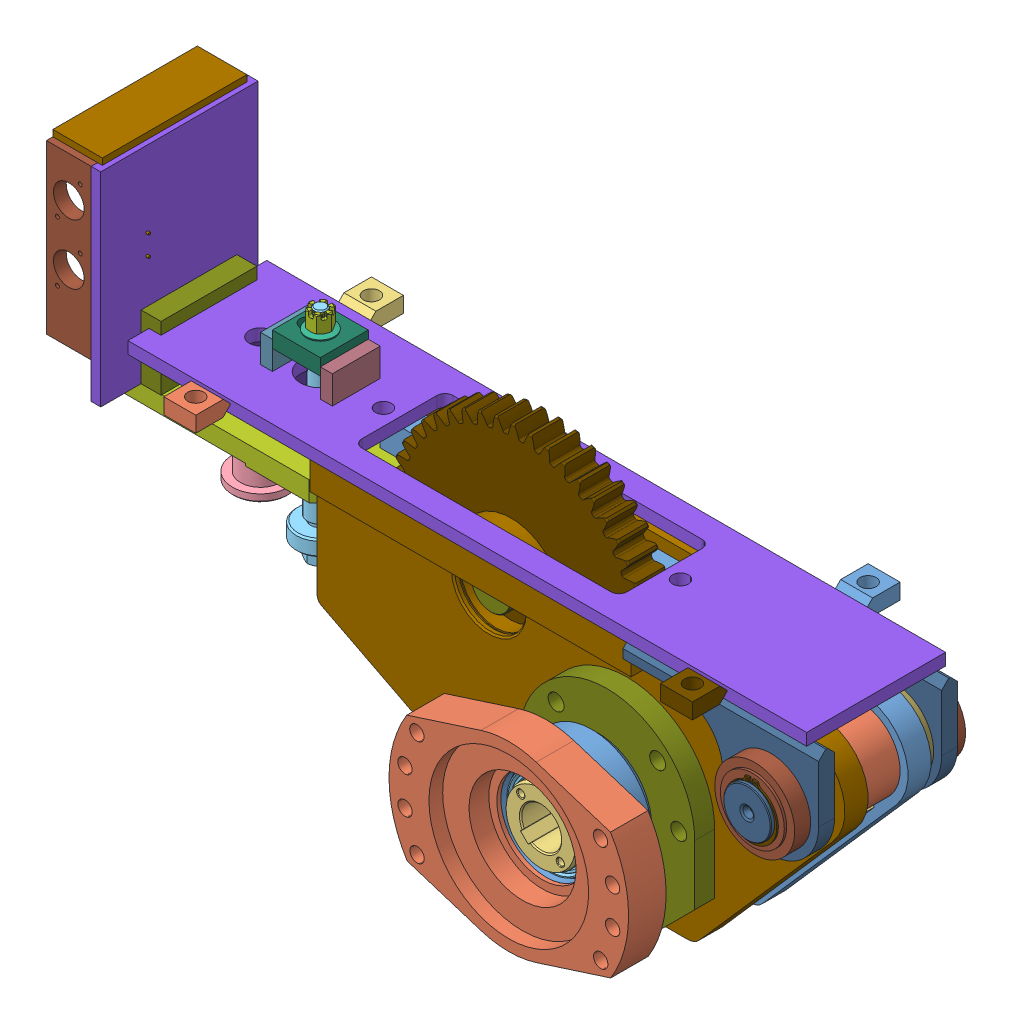
SolidWorks assembly g1_3_1_1, configuration 默认. Lengths in mm.
Overall size (943 530 331.8).
109 component instances, 72 part files, 43 mates.
Components (placement in the parent):
- g1_3_1_1_5_1-1: g1_3_1_1_5_1 [默认] at (308.7423 -95 30) x (-1 0 0) z (0 1 0) size (926 108 318.6)
  - g1_3_1_1_5-1_af1_1-1: g1_3_1_1_5-1_af1_1 [默认] at origin size (661 29 318.6)
  - g1_3_1_1_5-2_af0_1-1: g1_3_1_1_5-2_af0_1 [默认] at (-213.2 29 0) size (100 50 100)
  - g1_3_1_1_5-4_1-1: g1_3_1_1_5-4_1 [默认] at (-149.9151 54 -132.7301) x (0 1 0) z (-0.659692 0 0.751536) size (50 10 223)
  - g1_3_1_1_5-5_1-1: g1_3_1_1_5-5_1 [默认] at (20.5 54 -217) x (1 0 0) z (0 1 0) size (194 10 50)
  - g1_3_1_1_5-6_1-1: g1_3_1_1_5-6_1 [默认] at (248.4498 54 -161.5242) x (0 1 0) z (0.890083 0 0.455798) size (50 10 284)
  - g1_3_1_1_5-7_1-1: g1_3_1_1_5-7_1 [默认] at (377.8 54 -43.9) x (0 0 -1) z (0 1 0) size (87 10 50)
  - g1_3_1_1_5-9_af0_1-1: g1_3_1_1_5-9_af0_1 [默认] at (502.8 54 24.6) x (1 0 0) z (0 1 0) size (300 25 108)
  - g1_3_1_1_5-8_1-1: g1_3_1_1_5-8_1 [默认] at (437.8 54 49.6) x (1 0 0) z (0 1 0) size (60 50 60)
  - g1_3_1_1_5-1_af0_1-1: g1_3_1_1_5-1_af0_1 [默认] at (0 79 0) size (661 29 318.6)
- g1_3_1_1_4_1-1: g1_3_1_1_4_1 [默认] at (521.9423 -95 -33.3) x (1 0 0) z (0 -1 0) size (80 234 80)
  - g1_3_1_1_4-1_1-1: g1_3_1_1_4-1_1 [默认] at origin size (60 234 60.04)
  - g1_3_1_1_4-3_1-2: g1_3_1_1_4-3_1 [默认] at (0 224.3 0) size (80 3 80)
  - g1_3_1_1_4-2_1-1: g1_3_1_1_4-2_1 [默认] at (0 174.3 0) size (72 50 72)
  - g1_3_1_1_4-2_1-2: g1_3_1_1_4-2_1 [默认] at (0 9.7 0) size (72 50 72)
  - g1_3_1_1_4-2_1-3: g1_3_1_1_4-2_1 [默认] at (0 62.7 0) size (72 50 72)
  - g1_3_1_1_4-2_1-4: g1_3_1_1_4-2_1 [默认] at (0 121.3 0) size (72 50 72)
- g1_3_1_1_2_1-1: g1_3_1_1_2_1 [默认] at (308.7423 -195.4 0) x (0.999998 0.002137 0) z (0.002137 -0.999998 0) size (219.6 152 245)
  - g1_3_1_1_2-1_1-1: g1_3_1_1_2-1_1 [默认] at origin size (219.6 61 245)
  - g1_3_1_1_2-2_1-1: g1_3_1_1_2-2_1 [默认] at (0 152 0) x (-0.047609 0 0.998866) z (0 1 0) size (120.16 120.16 117)
  - g1_3_1_1_2-3_1-1: g1_3_1_1_2-3_1 [默认] at (-20.1525 129 20.1525) x (0 -1 0) z (0.707107 0 0.707107) size (28 11 14)
- g1_3_1_1_3_1-1: g1_3_1_1_3_1 [默认] at (135.9423 -78.4 83.75) x (0 0 -1) z (0 -1 0) size (103.5 321.87 322.01)
  - g1_3_1_1_3-1_1-1: g1_3_1_1_3-1_1 [默认] at origin size (103.5 52 52)
  - 16x10x45_gb1096_1-1: 16x10x45_gb1096_1 [默认] at (-0.5 0 25) x (1 0 0) z (0 0 -1) size (45 16 10)
  - _X2_60F08F6E_X0_g1_3_1_1_3-2_1-1: _X2_60F08F6E_X0_g1_3_1_1_3-2_1 [默认] at (25 0 0) x (0 0 1) z (1 0 0) size (322.01 321.87 50.08)
- g1_3_1_1_1_2-1: g1_3_1_1_1_2 [默认] at (308.7423 -195.4 123.8) x (0.999998 0.002137 0) z (0.002137 -0.999998 0) size (300 165.8 228)
  - g1_3_1_1_1_1_1-1: g1_3_1_1_1_1_1 [默认] at origin size (300 112 228)
    - g1_3_1_1_1_1-2_af0_1-1: g1_3_1_1_1_1-2_af0_1 [默认] at (0 50 0) size (150 65 150)
    - g1_3_1_1_1_1-3_af0_1-1: g1_3_1_1_1_1-3_af0_1 [默认] at (0 140 0) size (300 47 228)
  - g1_3_1_1_1-2_1-1: g1_3_1_1_1-2_1 [默认] at (0 122.2 0) x (0.707107 0 0.707107) z (0.707107 0 -0.707107) size (90 126 90)
  - g1_3_1_1_1-1_1-1: g1_3_1_1_1-1_1 [默认] at (0 77 0) x (0 1 0) z (0 0 1) size (20 110 110)
  - b90x110x12_gb9877_1_1-1: b90x110x12_gb9877_1_1 [默认] at (0 66.9 0) size (108.6 17.9 108.6)
    - b90x110x12_gb9877_1_rubber_1-1: b90x110x12_gb9877_1_rubber_1 [默认] at origin size (108.6 12 108.6)
    - b90x110x12_gb9877_1_frame_1-1: b90x110x12_gb9877_1_frame_1 [默认] at (0 -2.4 0) x (-1 0 0) z (0 0 1) size (107.2 9.5 107.2)
  - b90x110x12_gb9877_1_1-2: b90x110x12_gb9877_1_1 [默认] at (0 104.8 0) size (108.6 17.9 108.6)
    - b90x110x12_gb9877_1_rubber_1-1: b90x110x12_gb9877_1_rubber_1 [默认] at origin size (108.6 12 108.6)
    - b90x110x12_gb9877_1_frame_1-1: b90x110x12_gb9877_1_frame_1 [默认] at (0 -2.4 0) x (-1 0 0) z (0 0 1) size (107.2 9.5 107.2)
  - 80_gb894_1_1-1: 80_gb894_1_1 [默认] at (-2.4 11.1 -38.1746) x (1 0 0) z (0 -1 0) size (85.83 90.87 2.5)
- g1_3_1_1_6_1-1: g1_3_1_1_6_1 [默认] at (135.9423 0 84) x (-1 0 0) z (0 0 1) size (875 200 260)
  - g1_3_1_1_6-4_af0_1-1: g1_3_1_1_6-4_af0_1 [默认] at origin size (850 15 174)
  - g1_3_1_1_6-8_1-1: g1_3_1_1_6-8_1 [默认] at (0 40 57) x (1 0 0) z (0 -1 0) size (402 20 44.8)
  - g1_3_1_1_6-8_1-2: g1_3_1_1_6-8_1 [默认] at (0 40 -77) x (1 0 0) z (0 -1 0) size (402 20 44.8)
  - g1_3_1_1_6-1_1-1: g1_3_1_1_6-1_1 [默认] at (-386 95 -87) x (1 0 0) z (0 -1 0) size (245 20 140)
  - g1_3_1_1_6-1_1-2: g1_3_1_1_6-1_1 [默认] at (-386 95 67) x (1 0 0) z (0 -1 0) size (245 20 140)
  - g1_3_1_1_6-3_1-1: g1_3_1_1_6-3_1 [默认] at (-386 95 87) x (-1 0 0) z (0 1 0) size (100 20 100)
  - g1_3_1_1_6-3_1-2: g1_3_1_1_6-3_1 [默认] at (-386 95 -107) x (-1 0 0) z (0 1 0) size (100 20 100)
  - g1_3_1_1_6-2_1-1: g1_3_1_1_6-2_1 [默认] at (-386 95 57) x (-1 0 0) z (0 1 0) size (100 10 100)
  - g1_3_1_1_6-2_1-2: g1_3_1_1_6-2_1 [默认] at (-386 95 -57) x (1 0 0) z (0 1 0) size (100 10 100)
  - g1_3_1_1_6-9_1-1: g1_3_1_1_6-9_1 [默认] at (220 -17 0) x (0 1 0) z (0 0 -1) size (35 15 60)
  - g1_3_1_1_6-9_af0_1-1: g1_3_1_1_6-9_af0_1 [默认] at (310 -17 0) x (0 1 0) z (0 0 1) size (35 15 60)
  - g1_3_1_1_6-10_1-1: g1_3_1_1_6-10_1 [默认] at (265 -45 0) size (60 20 60)
  - g1_3_1_1_6-12_af0_1-1: g1_3_1_1_6-12_af0_1 [默认] at (434 25 0.5) x (0 0 1) z (0 -1 0) size (120 25 80)
  - g1_3_1_1_6-11_af0_1-1: g1_3_1_1_6-11_af0_1 [默认] at (357 15 0) size (94 40 60)
  - g1_3_1_1_6-5_af0_1-1: g1_3_1_1_6-5_af0_1 [默认] at (-311 -5 108.5) x (0 0 -1) z (1 0 0) size (43 19.6 40)
  - g1_3_1_1_6-5_af1_1-1: g1_3_1_1_6-5_af1_1 [默认] at (-311 -5 -108.5) x (0 0 1) z (-1 0 0) size (43 19.6 40)
  - g1_3_1_1_6-5_af2_1-1: g1_3_1_1_6-5_af2_1 [默认] at (311 -5 108.5) x (0 0 -1) z (1 0 0) size (43 19.6 40)
  - g1_3_1_1_6-5_af3_1-1: g1_3_1_1_6-5_af3_1 [默认] at (311 -5 -108.5) x (0 0 1) z (-1 0 0) size (43 19.6 40)
- g1_3_1_1-1_1-1: g1_3_1_1-1_1 [默认] at (-204.0577 -45.5 84) x (0.999708 0 0.02418) z (0.02418 0 -0.999708) size (70 135 70)
- g1_3_1_1_7_1-1: g1_3_1_1_7_1 [默认] at (-129.0577 -16.0167 84) x (0 1 0) z (0.020278 0 0.999794) size (272.02 60 60)
  - g1_3_1_1_7-1_1-1: g1_3_1_1_7-1_1 [默认] at origin size (272.02 60 60)
  - a35_5_gb1972_1-1: a35_5_gb1972_1 [默认] at (39.2167 0 0) x (0 0.075145 0.997173) z (0 0.997173 -0.075145) size (35.5 7.2 35.5)
  - a35_5_gb1972_1-2: a35_5_gb1972_1 [默认] at (62.8167 0 0) x (0 -0.99777 0.066751) z (0 -0.066751 -0.99777) size (35.5 7.2 35.5)
  - m16a_gb6178_1-1: m16a_gb6178_1 [默认] at (85.8167 13.8564 0) x (0 -1 0) z (-1 0 0) size (27.71 24 20.8)
- g1_3_1_1_8_1-1: g1_3_1_1_8_1 [默认] at (-293.0577 62.5 96.5) x (0 0 -1) z (0 1 0) size (197 71 268.3)
  - g1_3_1_1_8_1_af0_1-1: g1_3_1_1_8_1_af0_1 [默认] at origin size (197 68 263)
    - g1_3_1_1_8_1-3_af1_1-1: g1_3_1_1_8_1-3_af1_1 [默认] at origin size (197 12 255)
    - g1_3_1_1_8_1-1_1-1: g1_3_1_1_8_1-1_1 [默认] at (0 37 127.5) x (1 0 0) z (0 -1 0) size (181 8 62)
    - g1_3_1_1_8_1-2_af1_1-1: g1_3_1_1_8_1-2_af1_1 [默认] at (98.5 40 22.5) x (0 1 0) z (0 0 1) size (56 16 210)
    - g1_3_1_1_8_1-2_af0_1-1: g1_3_1_1_8_1-2_af0_1 [默认] at (-98.5 40 22.5) x (0 1 0) z (0 0 -1) size (56 16 210)
    - g1_3_1_1_8_1-5_1-1: g1_3_1_1_8_1-5_1 [默认] at (0 40 -82.5) x (1 0 0) z (0 1 0) size (165 8 56)
    - g1_3_1_1_8_1-6_1-1: g1_3_1_1_8_1-6_1 [默认] at (27.5 40 -106) x (0 1 0) z (0 0 -1) size (56 6 31)
    - g1_3_1_1_8_1-6_1-2: g1_3_1_1_8_1-6_1 [默认] at (-8.5 40 -106) x (0 1 0) z (0 0 -1) size (56 6 31)
    - g1_3_1_1_8_1-4_af1_1-1: g1_3_1_1_8_1-4_af1_1 [默认] at (-10 12 5) size (105 17 85)
    - g1_3_1_1_8_1-8_af0_1-1: g1_3_1_1_8_1-8_af0_1 [默认] at (12.5 40 -127.5) x (0 1 0) z (1 0 0) size (56 6 54)
  - g1_3_1_1_8-3_1-1: g1_3_1_1_8-3_1 [默认] at (12.5 37 -32.7987) x (0 0 -1) z (0 1 0) size (229 15 15)
  - g1_3_1_1_8-6_1-1: g1_3_1_1_8-6_1 [默认] at (12.5 37 30.1) x (-1 0 0) z (0 1 0) size (26 60 26)
  - g1_3_1_1_8-5_1-1: g1_3_1_1_8-5_1 [默认] at (12.5 29 -27.5) size (60 24 20)
  - g1_3_1_1_8-9_af0_1-1: g1_3_1_1_8-9_af0_1 [默认] at (-42.5 17 5.5) size (34 10 74)
  - g1_3_1_1_8-10_1-1: g1_3_1_1_8-10_1 [默认] at (12.5 37 -127.5) x (1 0 0) z (0 1 0) size (40 2 32)
  - ya2x20x90-2_gb2089_af0_1-1: ya2x20x90-2_gb2089_af0_1 [默认] at (12.5 37 -82.5) x (0 0 -1) z (1 0 0) size (92.3 24.62 24.71)
  - 14x2_65_gb3452_1_1-1: 14x2_65_gb3452_1_1 [默认] at (12.5 37 -124.5) x (0 0 1) z (0 1 0) size (2.65 19.37 19.38)
  - 15_gb894_1_1-1: 15_gb894_1_1 [默认] at (12 29.8675 -73.9) size (17.18 18.67 1.11)
  - 15_gb894_1_1-2: 15_gb894_1_1 [默认] at (12 29.8675 29) size (17.18 18.67 1.11)
  - 8_gb93_1-1: 8_gb93_1 [默认] at (32.5 53 -27.5) x (-1 0 0) z (0 1 0) size (12.3 12.3 2.1)
  - m8x40_gb5782_1-1: m8x40_gb5782_1 [默认] at (32.5 55.1 -27.5) size (15.01 45.3 13)
  - 8_gb93_1-2: 8_gb93_1 [默认] at (-7.5 53 -27.5) x (-1 0 0) z (0 1 0) size (12.3 12.3 2.1)
  - m8x40_gb5782_1-2: m8x40_gb5782_1 [默认] at (-7.5 55.1 -27.5) size (15.01 45.3 13)
  - m3x10_gb818_1-1: m3x10_gb818_1 [默认] at (57.5 2 60.5) size (5.81 12.5 5.77)
  - m3x10_gb818_1-2: m3x10_gb818_1 [默认] at (57.5 2 100.5) size (5.81 12.5 5.77)
  - m3x10_gb818_1-3: m3x10_gb818_1 [默认] at (-17.5 2 100.5) size (5.81 12.5 5.77)
  - m3x10_gb818_1-4: m3x10_gb818_1 [默认] at (-57.5 2 100.5) size (5.81 12.5 5.77)
  - m3x30_gb818_1-1: m3x30_gb818_1 [默认] at (-40.5 -3 7.5) size (5.81 32.5 5.77)
  - m3x30_gb818_1-2: m3x30_gb818_1 [默认] at (-40.5 -3 32.9) size (5.81 32.5 5.77)
  - 6_gb93_1-9: 6_gb93_1 [默认] at (-52.5 28.6 -17.5) x (1 0 0) z (0 -1 0) size (9.3 9.3 1.6)
  - m6x20_gb5783_1-9: m6x20_gb5783_1 [默认] at (-52.5 28.6 -17.5) size (11.55 24 10)
  - 6_gb93_1-10: 6_gb93_1 [默认] at (-32.5 28.6 -17.5) x (1 0 0) z (0 -1 0) size (9.3 9.3 1.6)
  - m6x20_gb5783_1-10: m6x20_gb5783_1 [默认] at (-32.5 28.6 -17.5) size (11.55 24 10)
  - 5x14_gb119_2_1-1: 5x14_gb119_2_1 [默认] at (-42.5 27 -3.5) size (5 14 5)
  - m3x6_gb818_1-1: m3x6_gb818_1 [默认] at (27.5 37 -123.5) x (1 0 0) z (0 1 0) size (5.81 8.5 5.77)
  - m3x6_gb818_1-2: m3x6_gb818_1 [默认] at (-2.5 37 -123.5) x (1 0 0) z (0 1 0) size (5.81 8.5 5.77)
- _X2_57AB5708_X0_16_gb93_1-9: _X2_57AB5708_X0_16_gb93_1 [默认] at (-305.0577 -50 44) x (0 0.924225 0.381849) z (-1 0 0) size (24.4 24.4 4.1)
- _X2_87BA6813_X0_m16x35_gb5783_10_1-1: _X2_87BA6813_X0_m16x35_gb5783_10_1 [默认] at (-309.1577 -50 44) x (0 -0.866025 -0.5) z (0 0.5 -0.866025) size (27.71 45 24)
- _X2_57AB5708_X0_16_gb93_1-10: _X2_57AB5708_X0_16_gb93_1 [默认] at (-305.0577 -50 124) x (0 0.924225 0.381849) z (-1 0 0) size (24.4 24.4 4.1)
- _X2_87BA6813_X0_m16x35_gb5783_10_1-2: _X2_87BA6813_X0_m16x35_gb5783_10_1 [默认] at (-309.1577 -50 124) x (0 -0.866025 -0.5) z (0 0.5 -0.866025) size (27.71 45 24)
- g1_3_1_1_1_1-1_af0_1-1: g1_3_1_1_1_1-1_af0_1 [默认] at (308.7423 -195.4 113) x (1 0 0) z (0 -1 0) size (220 42 245)
- g1_3_1_1_7-2_1-1: g1_3_1_1_7-2_1 [默认] at (-160.8119 -95.4 83.9778) x (1 0 0.0007) z (0 -1 0) size (63.51 55 25)
- g1_3_1_1_4-3_1-2: g1_3_1_1_4-3_1 [默认] at (521.9423 -95 -23.6) x (-0.923728 -0.383049 0) z (0.383049 -0.923728 0) size (80 3 80)
- 60_gb894_1_1-2: 60_gb894_1_1 [默认] at (523.8923 -66.5668 -28.6) x (-1 0 0) z (0 0 1) size (65.16 69.76 2)
- 60_gb894_1_1-3: 60_gb894_1_1 [默认] at (523.8923 -66.5668 194) x (-1 0 0) z (0 0 1) size (65.16 69.76 2)
Mates (geometry in assembly coordinates):
- 重合1: coincident anti-aligned: plane of g1_3_1_1_2_1-1/g1_3_1_1_2-3_1-1 through (283.6726 -210.6564 129) normal (-0.708616 0.705594 0); plane of g1_3_1_1_1_2-1/g1_3_1_1_1-2_1-1 through (283.4609 -210.869 246) normal (0.708616 -0.705594 0)
- 重合2: coincident anti-aligned: plane of g1_3_1_1_2_1-1/g1_3_1_1_2-2_1-1 through (308.7423 -195.4 120) normal (0 0 1); plane of g1_3_1_1_1_2-1/g1_3_1_1_1-2_1-1 through (308.7423 -195.4 120) normal (0 0 -1)
- 同心3: concentric aligned: cylinder of g1_3_1_1_2_1-1/g1_3_1_1_2-2_1-1 through (308.7423 -195.4 29.15) axis (0 0 1) radius 25; cylinder of g1_3_1_1_1_2-1/g1_3_1_1_1-2_1-1 through (308.7423 -195.4 246) axis (0 0 1) radius 25
- 同心9: concentric anti-aligned: cylinder of g1_3_1_1_8_1-1/g1_3_1_1_8_1_af0_1-1/g1_3_1_1_8_1-3_af1_1-1 through (-305.0577 -50 124) axis (1 0 0) radius 8.5; cylinder of _X2_87BA6813_X0_m16x35_gb5783_10_1-2 through (-272.4077 -50 124) axis (-1 0 0) radius 8
- 同心12: concentric anti-aligned: cylinder of g1_3_1_1_6_1-1/g1_3_1_1_6-12_af0_1-1 through (-249.5413 -50 44) axis (1 0 0) radius 7; cylinder of _X2_87BA6813_X0_m16x35_gb5783_10_1-1 through (-272.4077 -50 44) axis (-1 0 0) radius 8
- 同心13: concentric aligned: cylinder of _X2_57AB5708_X0_16_gb93_1-10 through (-305.0577 -50 124) axis (-1 0 0) radius 8.1; cylinder of _X2_87BA6813_X0_m16x35_gb5783_10_1-2 through (-272.4077 -50 124) axis (-1 0 0) radius 8
- 同心14: concentric aligned: cylinder of _X2_57AB5708_X0_16_gb93_1-9 through (-305.0577 -50 44) axis (-1 0 0) radius 8.1; cylinder of _X2_87BA6813_X0_m16x35_gb5783_10_1-1 through (-272.4077 -50 44) axis (-1 0 0) radius 8
- 重合3: coincident anti-aligned: plane of _X2_57AB5708_X0_16_gb93_1-9 through (-309.1577 -50 44) normal (-1 0 0); plane of _X2_87BA6813_X0_m16x35_gb5783_10_1-1 through (-309.1577 -50 44) normal (1 0 0)
- 重合4: coincident anti-aligned: plane of _X2_57AB5708_X0_16_gb93_1-10 through (-309.1577 -50 124) normal (-1 0 0); plane of _X2_87BA6813_X0_m16x35_gb5783_10_1-2 through (-309.1577 -50 124) normal (1 0 0)
- 同心15: concentric aligned: cylinder of g1_3_1_1_8_1-1/g1_3_1_1_8_1_af0_1-1/g1_3_1_1_8_1-3_af1_1-1 through (-305.0577 -50 44) axis (-1 0 0) radius 8.5; cylinder of _X2_87BA6813_X0_m16x35_gb5783_10_1-1 through (-272.4077 -50 44) axis (-1 0 0) radius 8
- 同心18: concentric aligned: cylinder of g1_3_1_1_6_1-1/g1_3_1_1_6-11_af0_1-1 through (-204.0577 71.0063 84) axis (0 -1 0) radius 14; cylinder of g1_3_1_1-1_1-1 through (-204.0577 -19.25 84) axis (0 -1 0) radius 15
- 同心20: concentric anti-aligned: cylinder of g1_3_1_1_5_1-1/g1_3_1_1_5-9_af0_1-1 through (-204.0577 -95.4 84) axis (0 1 0) radius 27; cylinder of g1_3_1_1-1_1-1 through (-204.0577 -50.5 84) axis (0 -1 0) radius 25
- 重合10: coincident anti-aligned: plane of g1_3_1_1_8_1-1/g1_3_1_1_8_1_af0_1-1/g1_3_1_1_8_1-3_af1_1-1 through (-305.0577 62.5 96.5) normal (-1 0 0); plane of _X2_57AB5708_X0_16_gb93_1-9 through (-305.0577 -50 44) normal (1 0 0)
- 重合12: coincident anti-aligned: plane of g1_3_1_1_8_1-1/g1_3_1_1_8_1_af0_1-1/g1_3_1_1_8_1-3_af1_1-1 through (-305.0577 62.5 96.5) normal (-1 0 0); plane of _X2_57AB5708_X0_16_gb93_1-10 through (-305.0577 -50 124) normal (1 0 0)
- 重合13: coincident anti-aligned: plane of g1_3_1_1_6_1-1/g1_3_1_1_6-12_af0_1-1 through (-293.0577 0 84) normal (-1 0 0); plane of g1_3_1_1_8_1-1/g1_3_1_1_8_1_af0_1-1/g1_3_1_1_8_1-3_af1_1-1 through (-293.0577 62.5 96.5) normal (1 0 0)
- 同心23: concentric aligned: cylinder of g1_3_1_1_5_1-1/g1_3_1_1_5-1_af1_1-1 through (521.9423 -95 30) axis (0 0 1) radius 36; cylinder of g1_3_1_1_6_1-1/g1_3_1_1_6-3_1-2 through (521.9423 -95 -23) axis (0 0 1) radius 36
- 同心24: concentric aligned: cylinder of g1_3_1_1_4_1-1/g1_3_1_1_4-2_1-2 through (521.9423 -95 -23.6) axis (0 0 1) radius 36; cylinder of g1_3_1_1_6_1-1/g1_3_1_1_6-3_1-2 through (521.9423 -95 -23) axis (0 0 1) radius 36
- 重合14: coincident anti-aligned: plane of g1_3_1_1_4_1-1/g1_3_1_1_4-3_1-2 through (521.9423 -95 191) normal (0 0 -1); plane of g1_3_1_1_6_1-1/g1_3_1_1_6-3_1-1 through (521.9423 -95 191) normal (0 0 1)
- 同心25: concentric aligned: cylinder of g1_3_1_1_5_1-1/g1_3_1_1_5-1_af1_1-1 through (135.9423 -78.4 30) axis (0 0 1) radius 45; cylinder of g1_3_1_1_3_1-1/g1_3_1_1_3-1_1-1 through (135.9423 -78.4 26.825) axis (0 0 1) radius 25
- 同心26: concentric aligned: cylinder of g1_3_1_1_5_1-1/g1_3_1_1_5-1_af1_1-1 through (308.7423 -195.4 30) axis (0 0 1) radius 75; cylinder of g1_3_1_1_2_1-1/g1_3_1_1_2-1_1-1 through (308.7423 -195.4 30) axis (0 0 1) radius 75
- 重合16: coincident anti-aligned: plane of g1_3_1_1_5_1-1/g1_3_1_1_5-1_af1_1-1 through (308.7423 -95 30) normal (0 0 -1); plane of g1_3_1_1_2_1-1/g1_3_1_1_2-1_1-1 through (308.7423 -195.4 30) normal (0 0 1)
- 重合17: coincident anti-aligned: plane of g1_3_1_1_5_1-1/g1_3_1_1_5-1_af1_1-1; plane of ? through (523.5275 -270.9624 278.2595) normal (0 -1 0)
- 重合19: coincident aligned: plane of g1_3_1_1_5_1-1/g1_3_1_1_5-1_af0_1-1 through (135.9423 -78.4 128.8) normal (0 0 1); plane of g1_3_1_1_3_1-1/g1_3_1_1_3-1_1-1 through (135.9423 -78.4 128.8) normal (0 0 1)
- 重合28: coincident anti-aligned: plane of g1_3_1_1_2_1-1/g1_3_1_1_2-1_1-1 through (308.7423 -195.4 0) normal (0 0 -1); plane of assembly through (0 0 0) normal (0 0 1)
- 重合31: coincident aligned: plane of g1_3_1_1_6_1-1/g1_3_1_1_6-4_af0_1-1 through (135.9423 0 84) normal (0 1 0); plane of assembly through (0 0 0) normal (0 1 0)
- 同心28: concentric aligned: cylinder of g1_3_1_1_6_1-1/g1_3_1_1_6-12_af0_1-1 through (-249.5413 -50 124) axis (-1 0 0) radius 7; cylinder of _X2_87BA6813_X0_m16x35_gb5783_10_1-2 through (-272.4077 -50 124) axis (-1 0 0) radius 8
- 同心29: concentric aligned: cylinder of g1_3_1_1_5_1-1/g1_3_1_1_5-1_af0_1-1 through (308.7423 -195.4 109) axis (0 0 1) radius 75; cylinder of g1_3_1_1_1_1-1_af0_1-1 through (308.7423 -195.4 -384.4109) axis (0 0 1) radius 75
- 同心30: concentric aligned: cylinder of g1_3_1_1_5_1-1/g1_3_1_1_5-1_af0_1-1 through (245.1423 -131.8 108.5324) axis (0 0 1) radius 5.1; cylinder of g1_3_1_1_1_1-1_af0_1-1 through (245.1423 -131.8 163) axis (0 0 1) radius 10
- 重合33: coincident anti-aligned: plane of g1_3_1_1_5_1-1/g1_3_1_1_5-1_af0_1-1 through (308.7423 -95 138) normal (0 0 1); plane of g1_3_1_1_1_1-1_af0_1-1 through (308.7423 -195.4 138) normal (0 0 -1)
- 平行2: parallel aligned: plane of ? through (593.4401 -66.5668 194.2) normal (1 0 0); plane of g1_3_1_1_6_1-1/g1_3_1_1_6-1_1-2 through (655.3901 -95 151) normal (1 0 0)
- 重合37: coincident anti-aligned: plane of g1_3_1_1_6_1-1/g1_3_1_1_6-11_af0_1-1 through (-174.0577 -50.5 114) normal (0 -1 0); plane of g1_3_1_1-1_1-1 through (-204.0577 -50.5 84) normal (0 1 0)
- 平行5: parallel anti-aligned: plane of g1_3_1_1_8_1-1/g1_3_1_1_8_1_af0_1-1/g1_3_1_1_8_1-5_1-1 through (-333.0577 -28 96.5) normal (0 -1 0); plane of _X2_87BA6813_X0_m16x35_gb5783_10_1-2 through (-309.1577 -38 130.9282) normal (0 1 0)
- 平行6: parallel anti-aligned: plane of g1_3_1_1_8_1-1/g1_3_1_1_8_1_af0_1-1/g1_3_1_1_8_1-5_1-1 through (-333.0577 -28 96.5) normal (0 -1 0); plane of _X2_87BA6813_X0_m16x35_gb5783_10_1-1 through (-309.1577 -38 50.9282) normal (0 1 0)
- 同心33: concentric anti-aligned: cylinder of g1_3_1_1_6_1-1/g1_3_1_1_6-10_1-1 through (-129.0577 45 84) axis (0 -1 0) radius 10; cylinder of g1_3_1_1_7_1-1/g1_3_1_1_7-1_1-1 through (-129.0577 -471.3188 84) axis (0 1 0) radius 8.9
- 同心34: concentric anti-aligned: cylinder of g1_3_1_1_7_1-1/g1_3_1_1_7-1_1-1 through (-129.0577 -471.3188 84) axis (0 1 0) radius 16; cylinder of g1_3_1_1_7-2_1-1 through (-129.0577 -95.4 84) axis (0 -1 0) radius 16.376
- 重合38: coincident anti-aligned: plane of g1_3_1_1_5_1-1/g1_3_1_1_5-8_1-1 through (-129.0577 -95.4 84) normal (0 -1 0); plane of g1_3_1_1_7-2_1-1 through (-160.8119 -95.4 83.9778) normal (0 1 0)
- 距离1: distance = 4 mm anti-aligned: plane of g1_3_1_1_7_1-1/g1_3_1_1_7-1_1-1 through (-129.0577 21 84) normal (0 1 0); plane of g1_3_1_1_6_1-1/g1_3_1_1_6-10_1-1 through (-129.0577 25 84) normal (0 -1 0)
- 重合40: coincident anti-aligned: plane of g1_3_1_1_4_1-1/g1_3_1_1_4-2_1-2 through (521.9423 -95 -23.6) normal (0 0 -1); plane of g1_3_1_1_4-3_1-2 through (521.9423 -95 -23.6) normal (0 0 1)
- 同心35: concentric anti-aligned: cylinder of g1_3_1_1_4_1-1/g1_3_1_1_4-1_1-1 through (521.9423 -95 -33.3) axis (0 0 1) radius 30; cylinder of g1_3_1_1_4-3_1-2 through (521.9423 -95 -23.6) axis (0 0 -1) radius 30.5
- 同心36: concentric aligned: cylinder of g1_3_1_1_4_1-1/g1_3_1_1_4-1_1-1 through (521.9423 -95 450.0941) axis (0 0 1) radius 28.5; cylinder of 60_gb894_1_1-2 through (521.9423 -95 -28.6) axis (0 0 1) radius 28.5
- 重合41: coincident anti-aligned: plane of g1_3_1_1_4-3_1-2 through (521.9423 -95 -26.6) normal (0 0 -1); plane of 60_gb894_1_1-2 through (523.8923 -66.5668 -26.6) normal (0 0 1)
- 重合42: coincident anti-aligned: plane of g1_3_1_1_4_1-1/g1_3_1_1_4-3_1-2 through (521.9423 -95 194) normal (0 0 1); plane of 60_gb894_1_1-3 through (523.8923 -66.5668 194) normal (0 0 -1)
- 同心37: concentric aligned: cylinder of g1_3_1_1_4_1-1/g1_3_1_1_4-1_1-1 through (521.9423 -95 -282.6941) axis (0 0 1) radius 28.5; cylinder of 60_gb894_1_1-3 through (521.9423 -95 194) axis (0 0 1) radius 28.5
